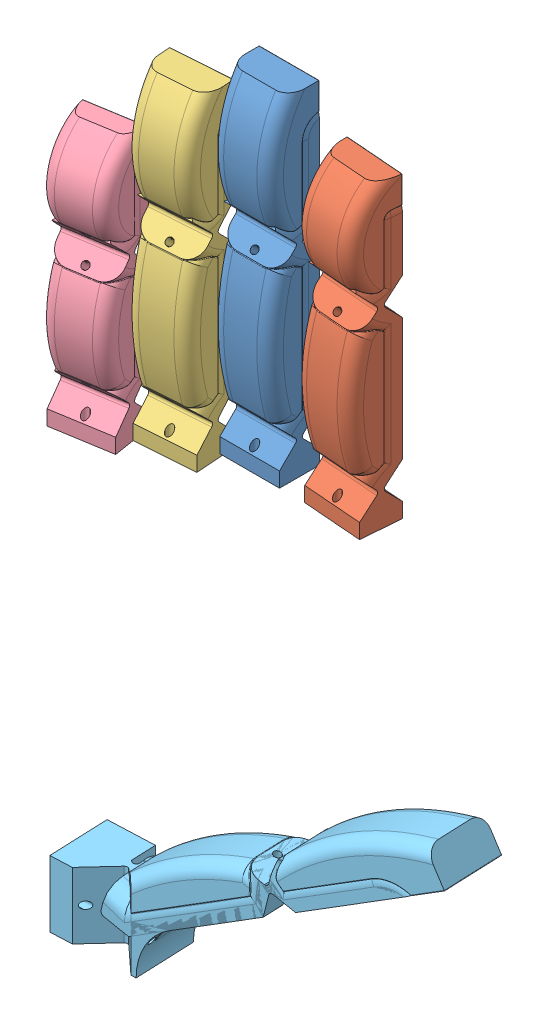
SolidWorks assembly HandAssembly, configuration Default. Lengths in mm.
Overall size (144.56 208.04 46.67).
25 component instances, 9 part files, 28 mates.
Components (placement in the parent):
- HandMasterSketch-1: HandMasterSketch [Default] at origin size (139.47 205.36 37.88) (hidden)
- MiddleFinger-1: MiddleFinger [Flat] at origin size (20.49 100.5 14.92)
- IndexFinger-1: IndexFinger [Flat] at (25.11 -0.88 -0.198) x (0.996917 0 0.078459) z (-0.078459 0 0.996917) size (20.49 90 15.29)
- RingFinger-2: RingFinger [Flat] at (-24.229 -7.25 1.722) x (0.997453 0 -0.071323) z (0.071323 0 0.997453) size (20.49 96.2 14.91)
- PinkyFinger-1: PinkyFinger [Flat] at (-46.46 -12.13 5.293) x (0.986771 0 -0.162121) z (0.162121 0 0.986771) size (20.49 78.7 15.55)
- Thumb-1: Thumb [Flat] at (-12.0392 -114.856 29.9501) x (0.040655 0 0.999173) z (-0.519374 0.854286 0.021133) size (20.49 131.74 30.08)
- Part2^HandAssembly-1: Part2^HandAssembly [Default] at origin size (120.02 129.41 59.78) (hidden, virtual)
- ServoAssem-1: ServoAssem [Default] at (-38.46 -26.63 -24.3814) x (1 0 0) z (0 -1 0) size (13.8 32.4 32) (hidden)
  - AGFRC Micro Servo-1: AGFRC Micro Servo [Default] at origin size (12 31.6 32)
  - Pulley-1: Pulley [Default] at (0 28.4 5.5) x (1 0 0) z (0 -1 0) size (13.8 13.8 4)
- ServoAssem-4: ServoAssem [Default] at (-20.229 -26.63 -24.3814) x (1 0 0) z (0 -1 0) size (13.8 32.4 32) (hidden)
  - AGFRC Micro Servo-1: AGFRC Micro Servo [Default] at origin size (12 31.6 32)
  - Pulley-1: Pulley [Default] at (0 28.4 5.5) x (1 0 0) z (0 -1 0) size (13.8 13.8 4)
- ServoAssem-5: ServoAssem [Default] at (-4 -26.63 -24.3814) x (1 0 0) z (0 -1 0) size (13.8 32.4 32) (hidden)
  - AGFRC Micro Servo-1: AGFRC Micro Servo [Default] at origin size (12 31.6 32)
  - Pulley-1: Pulley [Default] at (0 28.4 5.5) x (1 0 0) z (0 -1 0) size (13.8 13.8 4)
- ServoAssem-7: ServoAssem [Default] at (17.11 -26.63 -24.3814) x (1 0 0) z (0 -1 0) size (13.8 32.4 32) (hidden)
  - AGFRC Micro Servo-1: AGFRC Micro Servo [Default] at origin size (12 31.6 32)
  - Pulley-1: Pulley [Default] at (0 28.4 5.5) x (1 0 0) z (0 -1 0) size (13.8 13.8 4)
- ServoAssem-9: ServoAssem [Default] at (1.4 -114.356 -2.9814) x (0 0 -1) z (0 1 0) size (13.8 32.4 32) (hidden)
  - AGFRC Micro Servo-1: AGFRC Micro Servo [Default] at origin size (12 31.6 32)
  - Pulley-1: Pulley [Default] at (0 28.4 5.5) x (1 0 0) z (0 -1 0) size (13.8 13.8 4)
- ServoAssem-10: ServoAssem [Default] at (1.5 -77.13 -24.3814) x (0 -1 0) z (-1 0 0) size (13.8 32.4 32) (hidden)
  - AGFRC Micro Servo-1: AGFRC Micro Servo [Default] at origin size (12 31.6 32)
  - Pulley-1: Pulley [Default] at (0 28.4 5.5) x (1 0 0) z (0 -1 0) size (13.8 13.8 4)
Mates (geometry in assembly coordinates):
- Coincident1: coincident aligned: plane of HandMasterSketch-1 through (24.9399 0 1.9628) normal (0.996917 0 0.078459); plane of IndexFinger-1 through (25.11 -0.88 -0.198) normal (0.996917 0 0.078459)
- Coincident2: coincident aligned: plane of HandMasterSketch-1 through (0.1701 0 -2.1608) normal (-0.078459 0 0.996917); plane of IndexFinger-1 through (25.11 -0.88 -0.198) normal (-0.078459 0 0.996917)
- Coincident3: coincident aligned: plane of HandMasterSketch-1 through (0 -0.88 0) normal (0 1 0); plane of IndexFinger-1 through (25.11 -0.88 -0.198) normal (0 1 0)
- Coincident7: coincident aligned: plane of HandMasterSketch-1 through (-46.0856 0 7.5716) normal (0.986771 0 -0.162121); plane of PinkyFinger-1 through (-46.46 -12.13 5.293) normal (0.986771 0 -0.162121)
- Coincident8: coincident aligned: plane of HandMasterSketch-1 through (-0.3744 0 -2.2786) normal (0.162121 0 0.986771); plane of PinkyFinger-1 through (-46.46 -12.13 5.293) normal (0.162121 0 0.986771)
- Coincident9: coincident aligned: plane of HandMasterSketch-1 through (0 -12.13 0) normal (0 1 0); plane of PinkyFinger-1 through (-46.46 -12.13 5.293) normal (0 1 0)
- Coincident11: coincident aligned: plane of HandMasterSketch-1 through (-24.2283 0 1.7325) normal (0.997453 0 -0.071323); plane of RingFinger-2 through (-24.229 -7.25 1.722) normal (0.997453 0 -0.071323)
- Coincident12: coincident aligned: plane of HandMasterSketch-1 through (0 -7.25 0) normal (0 1 0); plane of RingFinger-2 through (-24.229 -7.25 1.722) normal (0 1 0)
- Coincident13: coincident aligned: plane of HandMasterSketch-1 through (-0.0007 0 -0.0105) normal (0.071323 0 0.997453); plane of RingFinger-2 through (-24.229 -7.25 1.722) normal (0.071323 0 0.997453)
- Coincident14: coincident aligned: plane of HandMasterSketch-1 through (-12.0392 -114.856 29.9501) normal (0.853579 0.519804 -0.034731); plane of Thumb-1 through (-12.0392 -114.856 29.9501) normal (0.853579 0.519804 -0.034731)
- Coincident17: coincident aligned: plane of HandMasterSketch-1 through (1.1967 0 29.4116) normal (0.040655 0 0.999173); plane of Thumb-1 through (-12.0392 -114.856 29.9501) normal (0.040655 0 0.999173)
- Coincident18: coincident aligned: plane of HandMasterSketch-1 through (47.3846 -77.9399 -1.928) normal (-0.519374 0.854286 0.021133); plane of Thumb-1 through (-12.0392 -114.856 29.9501) normal (-0.519374 0.854286 0.021133)
- Coincident41: coincident aligned: plane of ServoAssem-9/AGFRC Micro Servo-1 through (1.4 -114.356 3.0186) normal (0 0 1); plane of ServoAssem-10/AGFRC Micro Servo-1 through (1.5 -83.13 3.0186) normal (0 0 1)
- Coincident42: coincident aligned: plane of ServoAssem-1/AGFRC Micro Servo-1 through (-32.46 -26.63 3.0186) normal (0 0 1); plane of ServoAssem-10/AGFRC Micro Servo-1 through (1.5 -83.13 3.0186) normal (0 0 1)
- Coincident43: coincident aligned: plane of ServoAssem-4/AGFRC Micro Servo-1 through (-14.229 -26.63 3.0186) normal (0 0 1); plane of ServoAssem-10/AGFRC Micro Servo-1 through (1.5 -83.13 3.0186) normal (0 0 1)
- Coincident44: coincident aligned: plane of ServoAssem-5/AGFRC Micro Servo-1 through (2 -26.63 3.0186) normal (0 0 1); plane of ServoAssem-10/AGFRC Micro Servo-1 through (1.5 -83.13 3.0186) normal (0 0 1)
- Coincident45: coincident aligned: plane of ServoAssem-7/AGFRC Micro Servo-1 through (23.11 -26.63 3.0186) normal (0 0 1); plane of ServoAssem-10/AGFRC Micro Servo-1 through (1.5 -83.13 3.0186) normal (0 0 1)
- Coincident46: coincident aligned: plane of ServoAssem-5/AGFRC Micro Servo-1 through (2 -26.63 -24.3814) normal (0 1 0); plane of ServoAssem-7/AGFRC Micro Servo-1 through (23.11 -26.63 -24.3814) normal (0 1 0)
- Coincident47: coincident aligned: plane of ServoAssem-4/AGFRC Micro Servo-1 through (-14.229 -26.63 -24.3814) normal (0 1 0); plane of ServoAssem-7/AGFRC Micro Servo-1 through (23.11 -26.63 -24.3814) normal (0 1 0)
- Coincident48: coincident aligned: plane of ServoAssem-1/AGFRC Micro Servo-1 through (-32.46 -26.63 -24.3814) normal (0 1 0); plane of ServoAssem-7/AGFRC Micro Servo-1 through (23.11 -26.63 -24.3814) normal (0 1 0)
- Concentric2: concentric aligned: circle of HandMasterSketch-1; circle of ServoAssem-1/Pulley-1
- Concentric3: concentric aligned: circle of HandMasterSketch-1; circle of ServoAssem-4/Pulley-1
- Concentric4: concentric aligned: circle of HandMasterSketch-1; circle of ServoAssem-5/Pulley-1
- Concentric5: concentric aligned: circle of HandMasterSketch-1; circle of ServoAssem-7/Pulley-1
- Concentric6: concentric aligned: circle of HandMasterSketch-1; circle of ServoAssem-10/Pulley-1
- Coincident50: coincident: line of HandMasterSketch-1 through (12 -31 -102.856) axis (0 0 -1); plane of ServoAssem-9/Pulley-1 through (-31 -108.856 -4.0814) normal (-1 0 0)
- Coincident51: coincident: line of HandMasterSketch-1 through (4 -31 -108.856) axis (0 1 0); plane of ServoAssem-9/Pulley-1 through (-27 -108.856 -2.9814) normal (0 1 0)
- Parallel18: parallel anti-aligned: plane of ServoAssem-5/AGFRC Micro Servo-1 through (2 -49.63 -24.3814) normal (0 -1 0); plane of ServoAssem-10/AGFRC Micro Servo-1 through (1.5 -71.13 -24.3814) normal (0 1 0)
